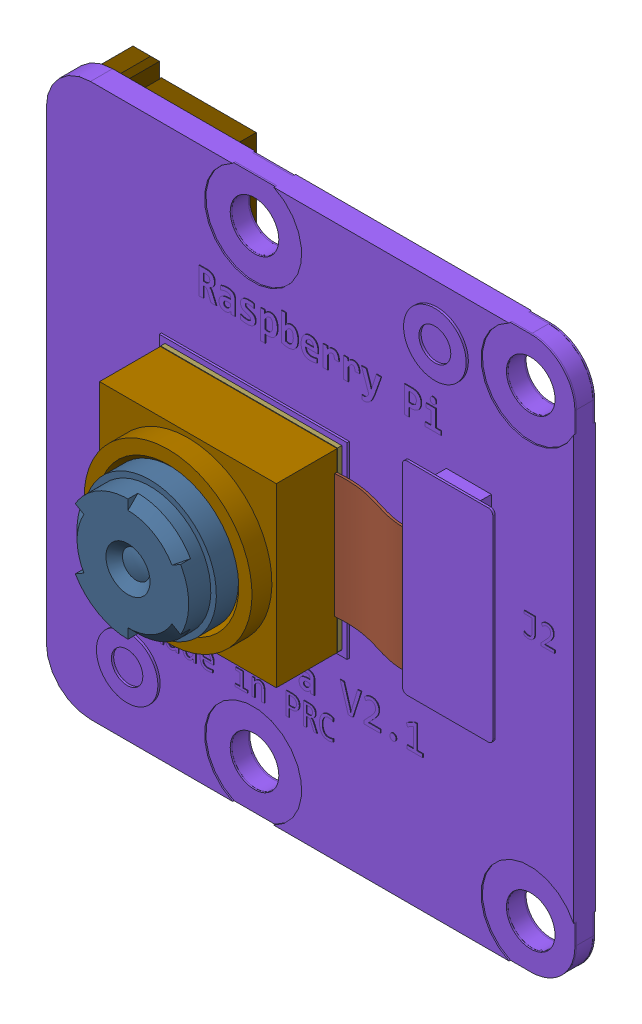
SolidWorks assembly RspCameraMia, configuration Default. Lengths in mm.
Overall size (23.86 25 9.96).
41 component instances, 22 part files, 0 mates.
Components (placement in the parent):
- RspCameraMia.stp-1: RspCameraMia.stp [Default] at origin size (23.86 25 9.96)
  - 70521906.stp-1: 70521906.stp [Default] at (1.7167 0.8597 0.0159) size (2 2.1 0.95)
    - 70521906_01.stp-1: 70521906_01.stp [Default] at origin size (0.25 0.55 0.75)
    - 70521906_02.stp-1: 70521906_02.stp [Default] at origin size (0.25 0.55 0.75)
    - 70521906_03.stp-1: 70521906_03.stp [Default] at origin size (2 1.25 0.9)
    - 70521906_04.stp-1: 70521906_04.stp [Default] at origin size (0.25 0.55 0.75)
    - 70521906_05.stp-1: 70521906_05.stp [Default] at origin size (0.25 0.55 0.75)
    - 70521906_06.stp-1: 70521906_06.stp [Default] at origin size (0.25 0.55 0.75)
    - 70521906_07.stp-1: 70521906_07.stp [Default] at origin size (0.25 0.55 0.75)
  - PicameraPCB.stp-1: PicameraPCB.stp [Default] at (0.2393 -0.0199 0) x (-1 0 0) z (0 0 1) size (23.86 25 2.2)
  - OVA5647_Housing.stp-1: OVA5647_Housing.stp [Default] at (-2.4078 0.0859 1) x (1 0 0) z (0 -1 0) size (8 3.95 8)
  - OVA5647_Lens_FOV.stp-1: OVA5647_Lens_FOV.stp [Default] at (-2.4087 0.0921 5.963) x (1 0 0) z (0 -1 0) size (6 3.35 6)
  - ribbon_cam.stp-1: ribbon_cam.stp [Default] at (-2.4804 0.3633 1.4162) x (0 1 0) z (1 0 0) size (5.6 0.69 4.76)
  - CCD.stp-1: CCD.stp [Default] at (-2.0757 0.287 1.296) x (1 0 0) z (0 -1 0) size (8.01 0.69 8.01)
  - CAPC-0805-T0.75-BN.stp-1: CAPC-0805-T0.75-BN.stp [Default] at (4.562 5.9833 -0.0026) x (0 -1 0) z (0 0 -1) size (2.1 1.35 0.75)
  - CAPC-0805-T0.75-BN.stp-2: CAPC-0805-T0.75-BN.stp [Default] at (2.0233 10.2705 -0.0026) x (0 -1 0) z (0 0 -1) size (2.1 1.35 0.75)
  - CAPC-0402-T0.55-BN.stp-1: CAPC-0402-T0.55-BN.stp [Default] at (-2.9562 6.224 -0.2572) x (-1 0 0) z (0 -1 0) size (1.05 0.55 0.55)
  - CAPC-0402-T0.55-BN.stp-2: CAPC-0402-T0.55-BN.stp [Default] at (-2.9504 5.2898 -0.2691) x (-1 0 0) z (0 -1 0) size (1.05 0.55 0.55)
  - CAPC-0402-T0.55-BN.stp-3: CAPC-0402-T0.55-BN.stp [Default] at (4.5768 -5.1833 -0.2811) x (-1 0 0) z (0 -1 0) size (1.05 0.55 0.55)
  - CAPC-0402-T0.55-BN.stp-4: CAPC-0402-T0.55-BN.stp [Default] at (2.5547 -5.1368 -0.2811) x (-1 0 0) z (0 -1 0) size (1.05 0.55 0.55)
  - CAPC-0402-T0.55-BN.stp-5: CAPC-0402-T0.55-BN.stp [Default] at (2.6129 -9.93 -0.293) x (-1 0 0) z (0 -1 0) size (1.05 0.55 0.55)
  - CAPC-0402-T0.55-BN.stp-6: CAPC-0402-T0.55-BN.stp [Default] at (4.7286 -9.9294 -0.293) x (-1 0 0) z (0 -1 0) size (1.05 0.55 0.55)
  - CAPC-0402-T0.55-BN.stp-7: CAPC-0402-T0.55-BN.stp [Default] at (8.4068 -3.8793 -0.2811) x (-1 0 0) z (0 -1 0) size (1.05 0.55 0.55)
  - CAPC-0402-T0.55-BN.stp-8: CAPC-0402-T0.55-BN.stp [Default] at (9.0088 0.0217 -0.2796) x (0 1 0) z (-1 0 0) size (1.05 0.55 0.55)
  - CAPC-0402-T0.55-BN.stp-9: CAPC-0402-T0.55-BN.stp [Default] at (10.4284 2.6731 -0.3022) x (0 1 0) z (-1 0 0) size (1.05 0.55 0.55)
  - CAPC-0402-T0.55-BN.stp-10: CAPC-0402-T0.55-BN.stp [Default] at (8.2321 1.3259 -0.2838) x (1 0 0) z (0 1 0) size (1.05 0.55 0.55)
  - RESC-0402.stp-1: RESC-0402.stp [Default] at (3.7919 0.0148 -0.0114) x (1 0 0) z (0 0 -1) size (1.05 0.55 0.4)
  - RESC-0402.stp-2: RESC-0402.stp [Default] at (4.1232 2.6296 -0.0028) x (0 -1 0) z (0 0 -1) size (1.05 0.55 0.4)
  - RESC-0402.stp-3: RESC-0402.stp [Default] at (10.5883 -6.2795 -0.0019) x (0 1 0) z (0 0 -1) size (1.05 0.55 0.4)
  - RESC-0603.stp-1: RESC-0603.stp [Default] at (-2.6191 7.0617 -0.0121) x (1 0 0) z (0 0 -1) size (1.7 0.9 0.55)
  - RESC-0603.stp-2: RESC-0603.stp [Default] at (-3.4466 3.0018 -0.0048) x (0 -1 0) z (0 0 -1) size (1.7 0.9 0.55)
  - RESC-1210.stp-1: RESC-1210.stp [Default] at (2.2265 5.9002 -0.0068) x (0 -1 0) z (0 0 -1) size (3.3 2.7 0.6)
  - c-1-1734248-5-e-raspberry_display.stp-1: c-1-1734248-5-e-raspberry_display.stp [Default] at (-10.6651 0.0449 -1.5) x (0 -1 0) z (-1 0 0) size (22.4 3.22 5.68)
  - SOT23-5.stp-1: SOT23-5.stp [Default] at (4.2989 9.8879 0.5457) x (0 -1 0) z (0 0 -1) size (2.84 3.03 1.19)
  - SOT23-5.stp-2: SOT23-5.stp [Default] at (3.5194 -3.2493 0.04) x (-1 0 0) z (0 0 -1) size (2.84 3.03 1.19)
  - SOT23-5.stp-3: SOT23-5.stp [Default] at (3.5816 -8.055 0.0206) x (-1 0 0) z (0 0 -1) size (2.84 3.03 1.19)
  - KX7 SMD Quartz Crystal Resonator 3.2x2.5mm.stp-1: KX7 SMD Quartz Crystal Resonator 3.2x2.5mm.stp [Default] at (9.9746 -4.9221 0.0339) x (-1 0 0) z (0 -1 0) size (3.2 0.6 2.5)
  - c6aaa.stp-1: c6aaa.stp [Default] at (0.0643 0.0942 0) x (1 0 0) z (0 0 -1) size (2 2.99 0.6)
  - 4pin_smd.stp-1: 4pin_smd.stp [Default] at (0.027 0.0676 0) x (1 0 0) z (0 0 -1) size (1.29 1 0.47)
  - 4pin_smd.stp-2: 4pin_smd.stp [Default] at (-0.0093 -6.0092 -0.0198) x (1 0 0) z (0 0 -1) size (1.29 1 0.47)
  - 4pin_smd.stp-3: 4pin_smd.stp [Default] at (0.0326 -3.0068 -0.0235) x (1 0 0) z (0 0 -1) size (1.29 1 0.47)
